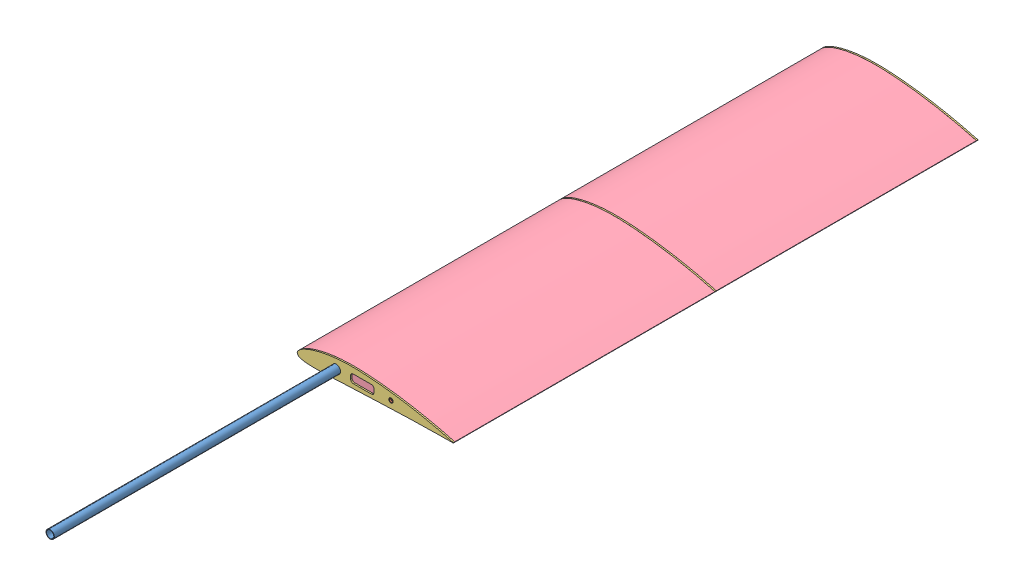
SolidWorks assembly WingRight, configuration Default. Lengths in mm.
Overall size (300.16 38.54 1558.4).
7 component instances, 4 part files, 16 mates.
Components (placement in the parent):
- CarbonTubeD16mmL1m-1: CarbonTubeD16mmL1m [Default] at (479.5115 365.1997 1534.9267) x (-0.043879 0.999037 0) z (0 0 1) size (16 16 1000)
- CarbonTubeD8mmL0.5m-1: CarbonTubeD8mmL0.5m [Default] at (584.5654 365.5466 1234.9267) x (-0.93506 -0.354488 0) z (0 0 1) size (8 8 500)
- polywoodRib300mm-1: polywoodRib300mm [Default] at (404.4705 354.8841 477.9267) size (300.16 38.54 2.8)
- XPSWingPart500mm-1: XPSWingPart500mm [Default] at (404.4705 354.8841 729.3267) size (300.16 38.54 500)
- polywoodRib300mm-2: polywoodRib300mm [Default] at (404.4705 354.8841 980.7267) size (300.16 38.54 2.8)
- XPSWingPart500mm-2: XPSWingPart500mm [Default] at (404.4705 354.8841 1232.1267) size (300.16 38.54 500)
- polywoodRib300mm-3: polywoodRib300mm [Default] at (404.4705 354.8841 1483.5267) size (300.16 38.54 2.8)
Mates (geometry in assembly coordinates):
- Совпадение1: coincident anti-aligned: plane of polywoodRib300mm-1 through (552.9013 350.6045 479.3267) normal (0 0 1); plane of XPSWingPart500mm-1 through (552.9013 350.6045 479.3267) normal (0 0 -1)
- Совпадение2: coincident aligned: circle of polywoodRib300mm-1; circle of XPSWingPart500mm-1
- Совпадение3: coincident aligned: line of polywoodRib300mm-1 through (404.5281 355.6298 479.3267) axis (-0.076973 -0.997033 0); line of XPSWingPart500mm-1 through (404.5281 355.6298 479.3267) axis (-0.076973 -0.997033 0)
- Совпадение4: coincident anti-aligned: plane of XPSWingPart500mm-1 through (552.9013 350.6045 979.3267) normal (0 0 1); plane of polywoodRib300mm-2 through (552.9013 350.6045 979.3267) normal (0 0 -1)
- Совпадение5: coincident aligned: circle of XPSWingPart500mm-1; circle of polywoodRib300mm-2
- Совпадение6: coincident aligned: line of XPSWingPart500mm-1 through (404.5281 355.6298 979.3267) axis (-0.076973 -0.997033 0); line of polywoodRib300mm-2 through (404.5281 355.6298 979.3267) axis (-0.076973 -0.997033 0)
- Совпадение7: coincident anti-aligned: plane of polywoodRib300mm-2 through (552.9013 350.6045 982.1267) normal (0 0 1); plane of XPSWingPart500mm-2 through (552.9013 350.6045 982.1267) normal (0 0 -1)
- Совпадение8: coincident aligned: circle of polywoodRib300mm-2; circle of XPSWingPart500mm-2
- Совпадение9: coincident aligned: line of polywoodRib300mm-2 through (404.5281 355.6298 982.1267) axis (-0.076973 -0.997033 0); line of XPSWingPart500mm-2 through (404.5281 355.6298 982.1267) axis (-0.076973 -0.997033 0)
- Совпадение10: coincident anti-aligned: plane of XPSWingPart500mm-2 through (552.9013 350.6045 1482.1267) normal (0 0 1); plane of polywoodRib300mm-3 through (552.9013 350.6045 1482.1267) normal (0 0 -1)
- Совпадение11: coincident aligned: circle of XPSWingPart500mm-2; circle of polywoodRib300mm-3
- Совпадение12: coincident aligned: line of XPSWingPart500mm-2 through (404.5281 355.6298 1482.1267) axis (-0.076973 -0.997033 0); line of polywoodRib300mm-3 through (404.5281 355.6298 1482.1267) axis (-0.076973 -0.997033 0)
- Концентричный1: concentric aligned: cylinder of CarbonTubeD8mmL0.5m-1 through (584.5654 365.5466 1484.9267) axis (0 0 -1) radius 4; cylinder of polywoodRib300mm-1 through (584.5654 365.5466 479.3267) axis (0 0 -1) radius 4.25
- Концентричный2: concentric aligned: cylinder of CarbonTubeD16mmL1m-1 through (479.5115 365.1997 2034.9267) axis (0 0 -1) radius 8; cylinder of polywoodRib300mm-1 through (479.5115 365.1997 479.3267) axis (0 0 -1) radius 8.25
- Расстояние1: distance = 550 mm aligned: plane of polywoodRib300mm-3 through (552.9013 350.6045 1484.9267) normal (0 0 1); plane of CarbonTubeD16mmL1m-1 through (479.5115 365.1997 2034.9267) normal (0 0 1)
- Совпадение15: coincident aligned: plane of CarbonTubeD8mmL0.5m-1 through (584.5654 365.5466 1484.9267) normal (0 0 1); plane of polywoodRib300mm-3 through (552.9013 350.6045 1484.9267) normal (0 0 1)
